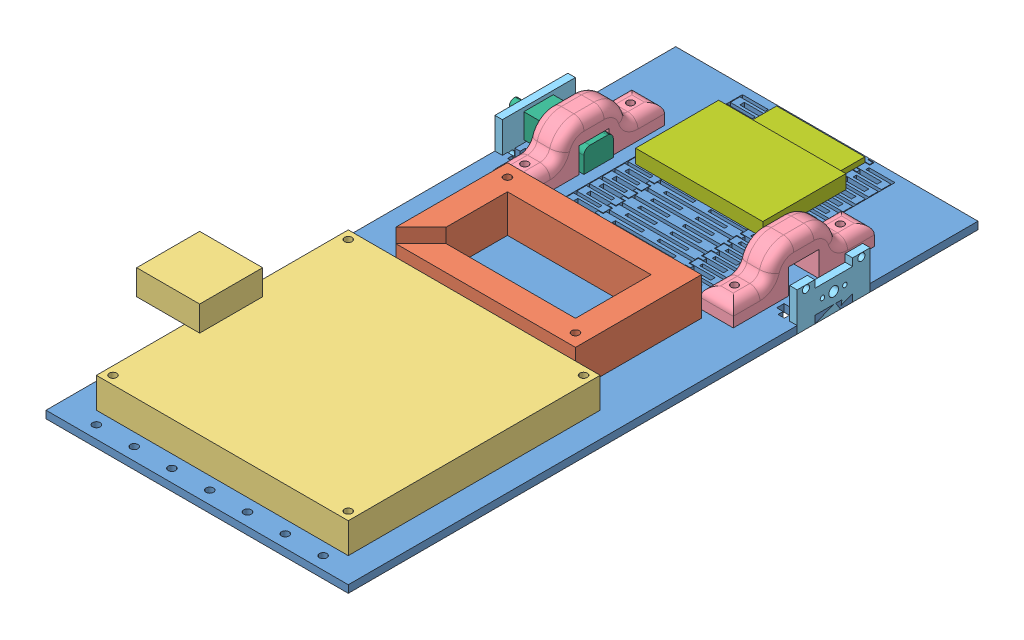
SolidWorks assembly project assembly, configuration Default. Lengths in mm.
Overall size (129 41 250).
9 component instances, 7 part files, 25 mates.
Components (placement in the parent):
- frame-1: frame [Default] at (121.0572 38.0684 213.649) size (120 2.97 250)
- battery bracket-1: battery bracket [Default] at (149.5572 56.0402 91.949) x (-1 0 0) z (0 0 1) size (79.83 15 52.83)
- pic_pcb-1: pic_pcb [Default] at (71.0572 41.0402 103.649) x (0 0 1) z (-1 0 0) size (100 22 119)
- motor_bracket-1: motor_bracket [Default] at (85.919 41.0402 20.949) x (0 0 1) z (0 -1 0) size (56 13 18)
- motor_bracket-2: motor_bracket [Default] at (169.1954 41.0402 20.949) x (0 0 1) z (0 -1 0) size (56 13 18)
- upright-1: upright [Default] at (64.029 38.0684 35.4415) x (0 1 0) z (-1 0 0) size (15.24 28.98 2.97)
- upright-2: upright [Default] at (181.0572 53.3084 6.4565) x (0 -1 0) z (-1 0 0) size (15.24 28.98 2.97)
- motor-1: motor [Default] at (72.919 42.1502 26.949) size (33.53 9.65 11.68)
- camera-1: camera [Default] at (145.9865 48.5402 14.0216) x (-1 0 0) z (0 0 1) size (50.5 26.5 48)
Mates (geometry in assembly coordinates):
- Parallel2: parallel: plane of frame-1 through (121.0572 41.0402 213.649) normal (0 1 0); plane of pic_pcb-1 through (71.0572 53.0402 103.649) normal (0 1 0)
- Coincident3: coincident: plane of frame-1 through (121.0572 41.0402 213.649) normal (0 1 0); plane of pic_pcb-1 through (71.0572 41.0402 103.649) normal (0 -1 0)
- Coincident6: coincident: plane of frame-1 through (121.0572 41.0402 213.649) normal (0 1 0); plane of motor_bracket-1 through (72.919 41.0402 26.949) normal (0 -1 0)
- Concentric2: concentric: cylinder of frame-1 through (79.419 41.0402 -0.051) axis (0 -1 0) radius 1.5; cylinder of motor_bracket-1 through (79.419 36.0402 -0.051) axis (0 1 0) radius 1.46
- Parallel3: parallel: plane of frame-1 through (121.0572 41.0402 213.649) normal (0 0 1); plane of motor_bracket-1 through (72.919 49.0402 48.949) normal (0 0 1)
- Concentric3: concentric: circle of frame-1; circle of pic_pcb-1
- Parallel5: parallel: plane of frame-1 through (121.0572 41.0402 213.649) normal (0 0 1); plane of pic_pcb-1 through (71.0572 53.0402 203.649) normal (0 0 1)
- Coincident11: coincident: plane of frame-1 through (121.0572 41.0402 213.649) normal (0 1 0); plane of motor_bracket-2 through (156.1954 41.0402 26.949) normal (0 -1 0)
- Concentric5: concentric: cylinder of frame-1 through (162.6954 41.0402 -0.051) axis (0 -1 0) radius 1.5; circle of motor_bracket-2
- Parallel6: parallel: plane of frame-1 through (181.0572 41.0402 213.649) normal (1 0 0); plane of motor_bracket-2 through (156.1954 41.0402 20.949) normal (-1 0 0)
- Coincident13: coincident: plane of frame-1 through (121.0572 41.0402 213.649) normal (0 1 0); plane of battery bracket-1 through (149.5572 41.0402 91.949) normal (0 -1 0)
- Parallel7: parallel: plane of frame-1 through (181.0572 41.0402 213.649) normal (1 0 0); plane of battery bracket-1 through (159.5572 41.0402 91.949) normal (1 0 0)
- Concentric6: concentric: circle of frame-1; circle of battery bracket-1
- Parallel8: parallel: plane of frame-1 through (121.0572 41.0402 6.4565) normal (0 0 1); plane of upright-1 through (61.0572 38.0684 6.4565) normal (0 0 -1)
- Coincident17: coincident: plane of frame-1 through (121.0572 38.0684 213.649) normal (0 -1 0); plane of upright-1 through (61.0572 38.0684 35.4415) normal (0 -1 0)
- Coincident18: coincident: plane of frame-1 through (121.0572 41.0402 6.4565) normal (0 0 1); plane of upright-1 through (61.0572 38.0684 6.4565) normal (0 0 -1)
- Coincident19: coincident: plane of frame-1 through (64.029 41.0402 213.649) normal (-1 0 0); plane of upright-1 through (64.029 38.0684 35.4415) normal (1 0 0)
- Coincident20: coincident: plane of frame-1 through (121.0572 41.0402 35.4415) normal (0 0 -1); plane of upright-2 through (178.0854 53.3084 35.4415) normal (0 0 1)
- Coincident21: coincident: plane of frame-1 through (121.0572 38.0684 213.649) normal (0 -1 0); plane of upright-2 through (178.0854 38.0684 6.4565) normal (0 -1 0)
- Coincident22: coincident: plane of frame-1 through (178.0854 41.0402 213.649) normal (1 0 0); plane of upright-2 through (178.0854 53.3084 6.4565) normal (-1 0 0)
- Coincident23: coincident: plane of motor_bracket-1 through (72.919 51.0402 14.949) normal (0 -1 0); plane of motor-1 through (72.919 51.0402 26.949) normal (0 1 0)
- Coincident24: coincident: plane of motor_bracket-1 through (72.919 51.0402 26.949) normal (0 0 -1); plane of motor-1 through (72.919 51.0402 26.949) normal (0 0 1)
- Coincident25: coincident: plane of upright-1 through (64.029 38.0684 35.4415) normal (1 0 0); plane of motor-1 through (64.029 51.8022 26.949) normal (-1 0 0)
- Coincident27: coincident: plane of frame-1 through (121.0572 41.0402 213.649) normal (0 1 0); plane of camera-1 through (145.9865 41.0402 14.0216) normal (0 -1 0)
- Parallel9: parallel: plane of frame-1 through (181.0572 41.0402 213.649) normal (1 0 0); plane of camera-1 through (145.9865 43.0402 14.0216) normal (1 0 0)
